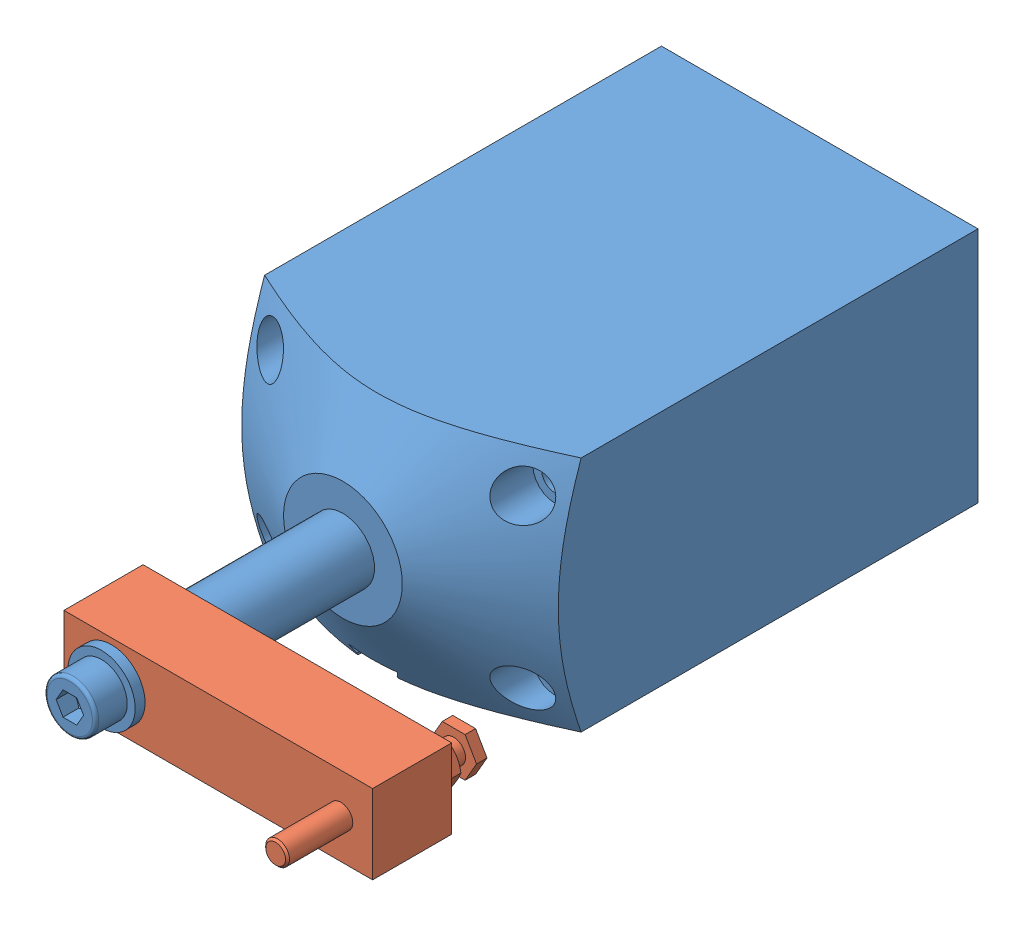
SolidWorks assembly Subconjunto Aperto 1875206CCW, configuration Default. Lengths in mm.
Overall size (106.05 79.39 195.5).
2 component instances, 2 part files, 3 mates.
Components (placement in the parent):
- 1875206BCCW.stp-1: 1875206BCCW.stp [Default] at (115.4005 -41.7141 238.6721) size (80.1 79.39 189.5)
- 0187526.stp-2: 0187526.stp [Default] at (115.4005 -41.7141 228.1721) size (78 20 47.65)
Mates (geometry in assembly coordinates):
- Concentric1: concentric aligned: cone of 1875206BCCW.stp-1 through (115.4005 -41.7141 226.1721) axis (0 0 1); cone of 0187526.stp-2 through (115.4005 -41.7141 228.1721) axis (0 0 1)
- Coincident1: coincident aligned: circle of 1875206BCCW.stp-1; plane of 0187526.stp-2 through (103.4005 -51.7141 208.1721) normal (0 0 -1)
- LimitAngle1: limit planar angle = 0 rad aligned: plane of 0187526.stp-2 through (181.4005 -31.7141 208.1721) normal (1 0 0); plane of 1875206BCCW.stp-1 through (155.4005 -71.7141 169.6721) normal (1 0 0)
